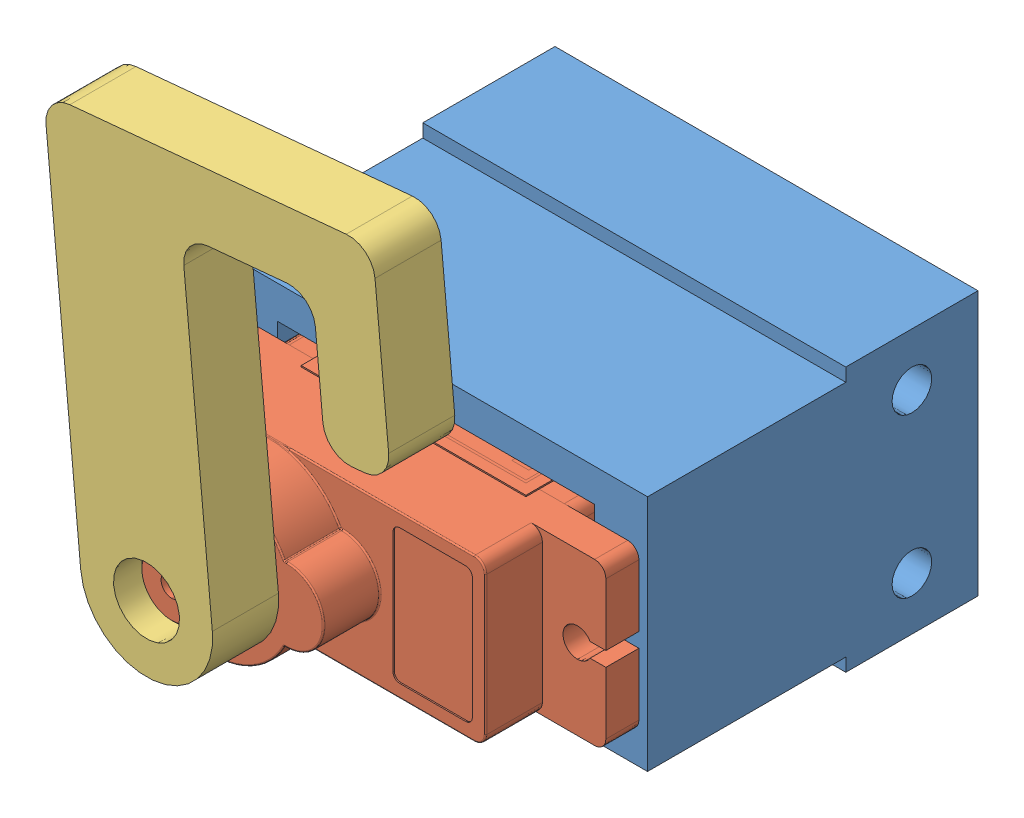
SolidWorks assembly Assemblage Servo-Support Servo, configuration Défaut. Lengths in mm.
Overall size (36.26 42.21 41.75).
3 component instances, 3 part files, 4 mates.
Components (placement in the parent):
- Support Servo-1: Support Servo [Défaut] at (-0.9587 0.0799 30) size (32 20 25)
- SG90 Servo-1: SG90 Servo [Défaut] at (-7.6319 27.8631 33.7322) x (1 0 0) z (0 -1 0) size (32.1 29.95 12.4)
- Crochet-1: Crochet [Défaut] at (-7.5154 15.0138 66.75) x (-0.093785 0.995592 0) z (0 0 1) size (35 30 5)
Mates (geometry in assembly coordinates):
- Coaxiale2: concentric aligned: circle of SG90 Servo-1; circle of Crochet-1
- Coïncidente5: coincident anti-aligned: plane of SG90 Servo-1 through (-6.1087 0.0799 66.75) normal (0 0 1); plane of Crochet-1 through (-6.1087 0.0799 66.75) normal (0 0 -1)
- Coaxiale3: concentric anti-aligned: circle of Support Servo-1; circle of SG90 Servo-1
- Coïncidente6: coincident anti-aligned: plane of Support Servo-1 through (-0.9587 0.0799 40) normal (0 0 1); plane of SG90 Servo-1 through (-11.3587 -5.1701 40) normal (0 0 -1)
